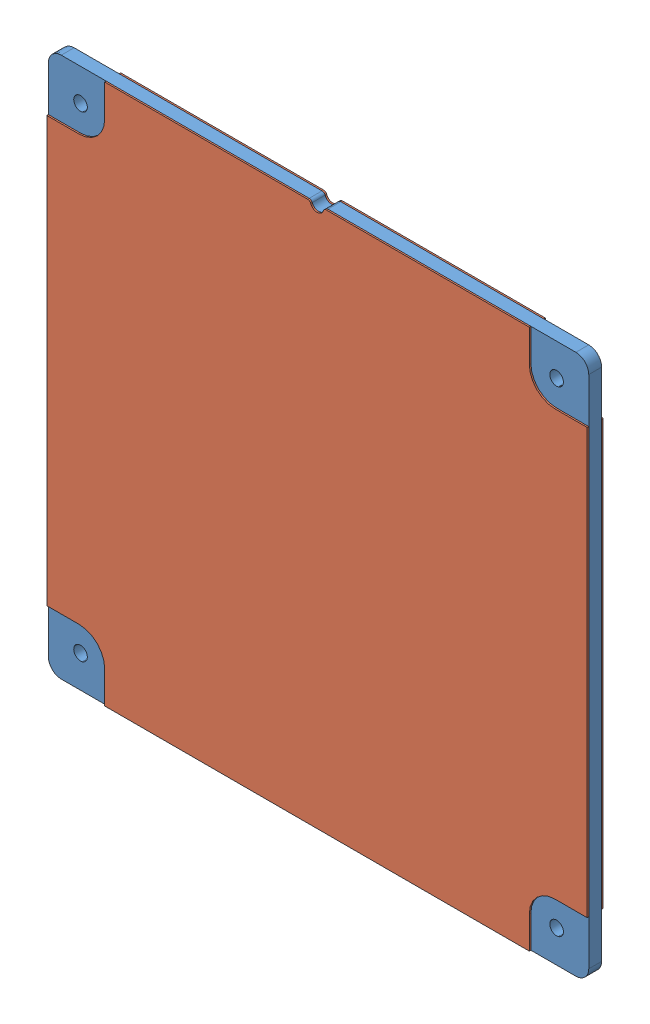
SolidWorks assembly FE-00083, configuration FE-00083-ID3. Lengths in mm.
Overall size (266.7 266.7 7.87).
3 component instances, 2 part files, 9 mates.
Components (placement in the parent):
- FE-00082-1: FE-00082 [Default] at (0 0 0.762) size (266.7 266.7 6.35)
- FE-00083-Vinyl-1: FE-00083-Vinyl [FE-00083-ID3-Vinyl] at (0 0 1.524) size (266.7 266.7 0.76)
- FE-00083-Vinyl-2: FE-00083-Vinyl [FE-00083-ID3-Vinyl] at (0 0 6.35) x (-1 0 0) z (0 0 -1) size (266.7 266.7 0.76)
Mates (geometry in assembly coordinates):
- Coincident1: coincident anti-aligned: plane of FE-00082-1 through (0 0 7.112) normal (0 0 1); plane of FE-00083-Vinyl-1 through (-133.35 133.35 7.112) normal (0 0 -1)
- Coincident2: coincident aligned: plane of FE-00082-1 through (133.35 -133.35 7.112) normal (1 0 0); plane of FE-00083-Vinyl-1 through (133.35 -133.35 7.874) normal (1 0 0)
- Coincident3: coincident aligned: plane of FE-00082-1 through (-133.35 133.35 7.112) normal (0 1 0); plane of FE-00083-Vinyl-1 through (-133.35 133.35 7.874) normal (0 1 0)
- Coincident4: coincident anti-aligned: plane of FE-00082-1 through (0 0 0.762) normal (0 0 -1); plane of FE-00083-Vinyl-2 through (133.35 133.35 0.762) normal (0 0 1)
- Coincident5: coincident aligned: plane of FE-00082-1 through (133.35 -133.35 7.112) normal (1 0 0); plane of FE-00083-Vinyl-2 through (133.35 -133.35 0) normal (1 0 0)
- Coincident6: coincident aligned: plane of FE-00082-1 through (-133.35 133.35 7.112) normal (0 1 0); plane of FE-00083-Vinyl-2 through (133.35 133.35 0) normal (0 1 0)
- Symmetric1: symmetric aligned: plane of FE-00082-1 through (-133.35 -133.35 7.112) normal (0 -1 0); plane of FE-00082-1 through (-133.35 133.35 7.112) normal (0 1 0)
- Symmetric2: symmetric aligned: plane of FE-00082-1 through (133.35 -133.35 7.112) normal (1 0 0); plane of FE-00082-1 through (-133.35 -133.35 7.112) normal (-1 0 0)
- Coincident7: coincident anti-aligned: plane of FE-00083-Vinyl-2 through (0 0 0) normal (0 0 -1)
